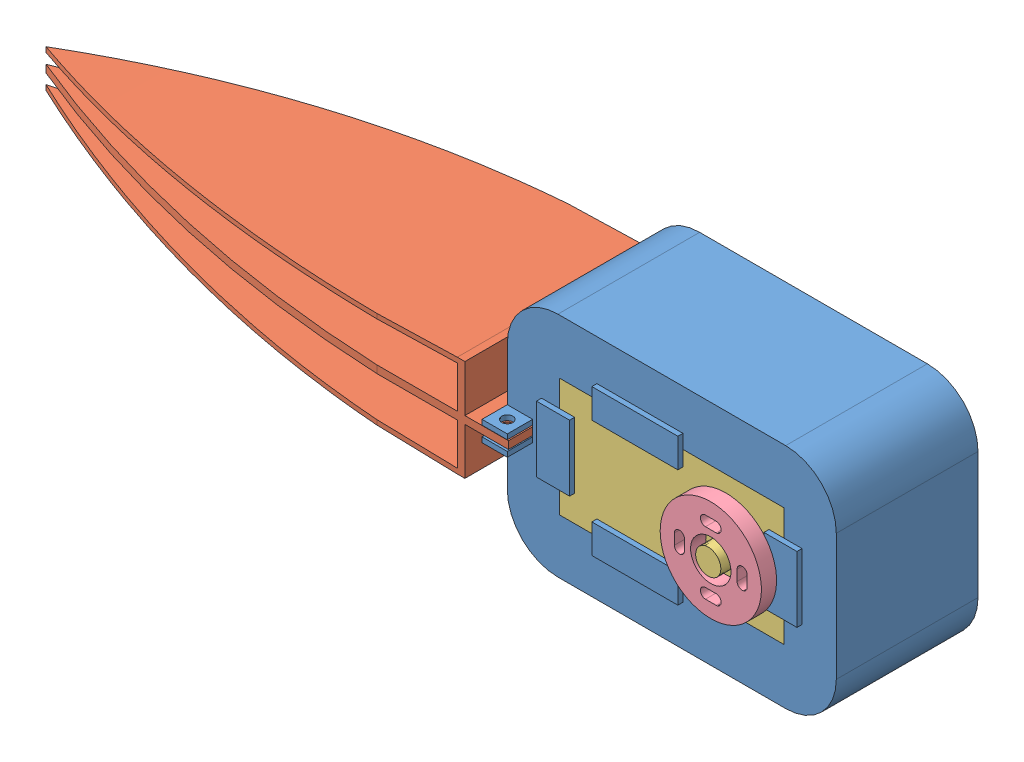
SolidWorks assembly bus_assembly_tail, configuration 預設. Lengths in mm.
Overall size (170.1 45 38.21).
5 component instances, 4 part files, 12 mates.
Components (placement in the parent):
- bus2_tail-2: bus2_tail [預設] at (-9.0934 -16.9047 37.067) size (65 45 38)
- bus_final_tail-2: bus_final_tail [預設] at (-73.1187 -16.9047 50.3365) x (-1 0 0.00071) z (0 1 0) size (110.1 38.13 25.31)
- bus_servo-4: bus_servo [預設] at (-16.5803 -28.3978 37.067) x (1 0 0) z (0 -1 0) size (44.4 38 23.4)
- bus_servo_cicrcle1-1: bus_servo_cicrcle1 [預設] at (-24.328 -16.9047 66.567) size (20 20 3)
- bus_servo_cicrcle1-2: bus_servo_cicrcle1 [預設] at (-24.328 -16.9047 32.567) size (20 20 3)
Mates (geometry in assembly coordinates):
- 重合/共線/共點11: coincident anti-aligned: plane of bus2_tail-2 through (-58.728 -28.6047 76.067) normal (0 1 0); plane of bus_servo-4 through (-58.728 -28.6047 65.067) normal (0 -1 0)
- 重合/共線/共點12: coincident anti-aligned: plane of bus2_tail-2 through (-14.328 -5.2047 76.067) normal (-1 0 0); plane of bus_servo-4 through (-14.328 -5.2047 65.067) normal (1 0 0)
- 重合/共線/共點13: coincident aligned: plane of bus2_tail-2 through (-9.0934 -16.9047 65.067) normal (0 0 1); plane of bus_servo-4 through (-16.5803 -28.3978 65.067) normal (0 0 1)
- 同軸心6: concentric anti-aligned: cylinder of bus2_tail-2 through (-66.528 -11.9047 67.567) axis (0 -1 0) radius 1.1; cylinder of bus_final_tail-2 through (-66.528 -17.6547 67.567) axis (0 1 0) radius 1.1
- 同軸心7: concentric anti-aligned: cylinder of bus2_tail-2 through (-66.528 -11.9047 34.567) axis (0 -1 0) radius 1.1; cylinder of bus_final_tail-2 through (-66.528 -17.6547 34.567) axis (0 1 0) radius 1.1
- 平行相距7: distance = 0.25 mm anti-aligned: plane of bus_final_tail-2 through (-73.1187 -17.6547 50.3365) normal (0 -1 0); plane of bus2_tail-2 through (-9.0934 -17.9047 37.067) normal (0 1 0)
- 同軸心9: concentric anti-aligned: cylinder of bus_servo-4 through (-24.328 -16.9047 65.067) axis (0 0 1) radius 2.5; cylinder of bus_servo_cicrcle1-1 through (-24.328 -16.9047 70.567) axis (0 0 -1) radius 4
- 平行4: parallel anti-aligned: plane of bus2_tail-2 through (-4.028 5.5953 65.067) normal (1 0 0); plane of bus_servo_cicrcle1-1 through (-17.128 -15.8547 70.567) normal (-1 0 0)
- 平行相距8: distance = 0.5 mm aligned: plane of bus_servo-4 through (-24.328 -16.9047 70.067) normal (0 0 1); plane of bus_servo_cicrcle1-1 through (-24.328 -16.9047 69.567) normal (0 0 1)
- 同軸心10: concentric anti-aligned: cylinder of bus_servo-4 through (-24.328 -16.9047 32.067) axis (0 0 1) radius 2.5; cylinder of bus_servo_cicrcle1-2 through (-24.328 -16.9047 36.567) axis (0 0 -1) radius 4
- 平行5: parallel anti-aligned: plane of bus2_tail-2 through (-4.028 5.5953 65.067) normal (1 0 0); plane of bus_servo_cicrcle1-2 through (-17.128 -15.8547 36.567) normal (-1 0 0)
- 平行相距10: distance = 0.5 mm aligned: plane of bus_servo-4 through (-24.328 -16.9047 32.067) normal (0 0 -1); plane of bus_servo_cicrcle1-2 through (-24.328 -16.9047 32.567) normal (0 0 -1)
